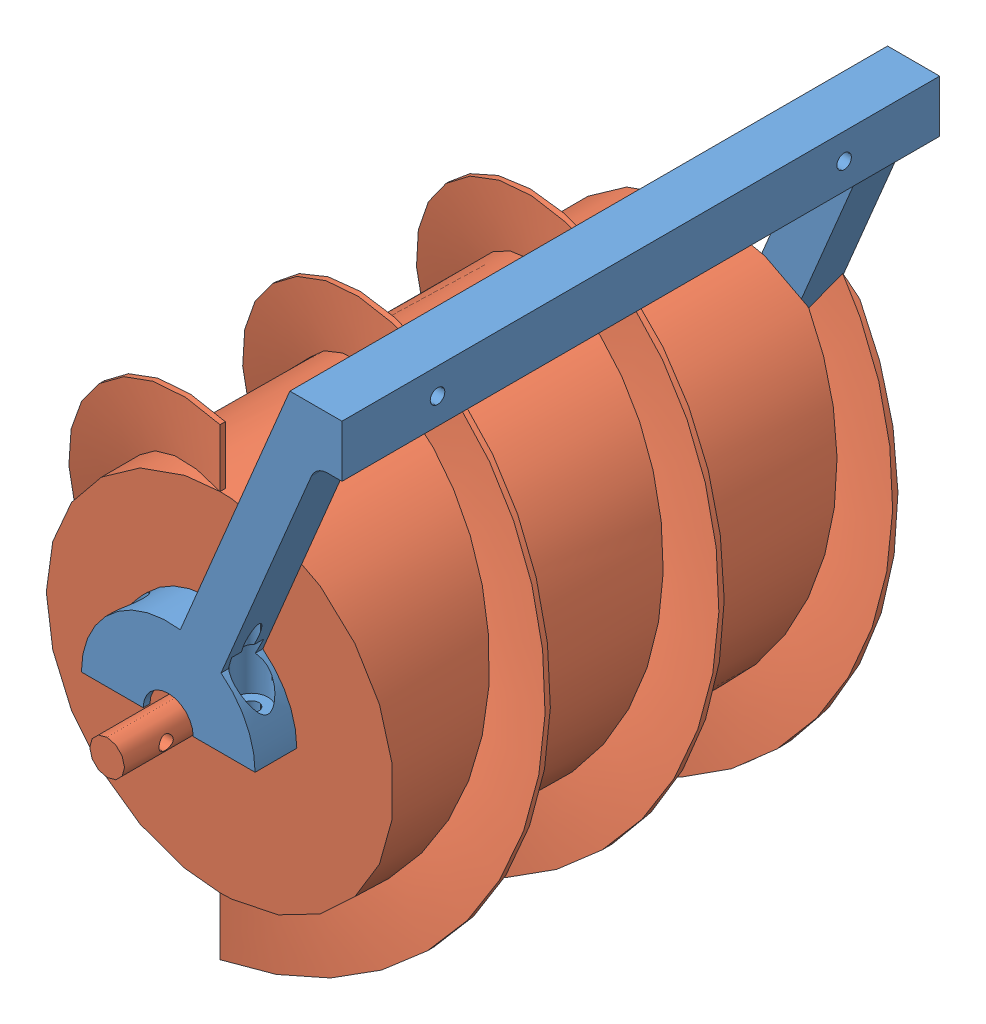
SolidWorks assembly Assem1, configuration Default. Lengths in mm.
Overall size (133.34 166.96 189.58).
2 component instances, 2 part files, 2 mates.
Components (placement in the parent):
- GSL_Feet_Right_GSL12-1: GSL_Feet_Right_GSL12 [Default] at (92.4243 183.2337 135.4838) size (133.3 166.65 172)
- HGSL2_CC-1: HGSL2_CC [Default] at (34.9243 90.7337 66.5638) size (133.34 133.91 174.84)
Mates (geometry in assembly coordinates):
- Distance1: distance = 5.08 mm: plane of GSL_Feet_Right_GSL12-1 through (77.4243 183.2337 61.4838) normal (0 0 1); plane of HGSL2_CC-1 through (34.9243 90.7337 66.5638) normal (0 0 -1)
- Concentric1: concentric: circle of GSL_Feet_Right_GSL12-1; circle of HGSL2_CC-1
